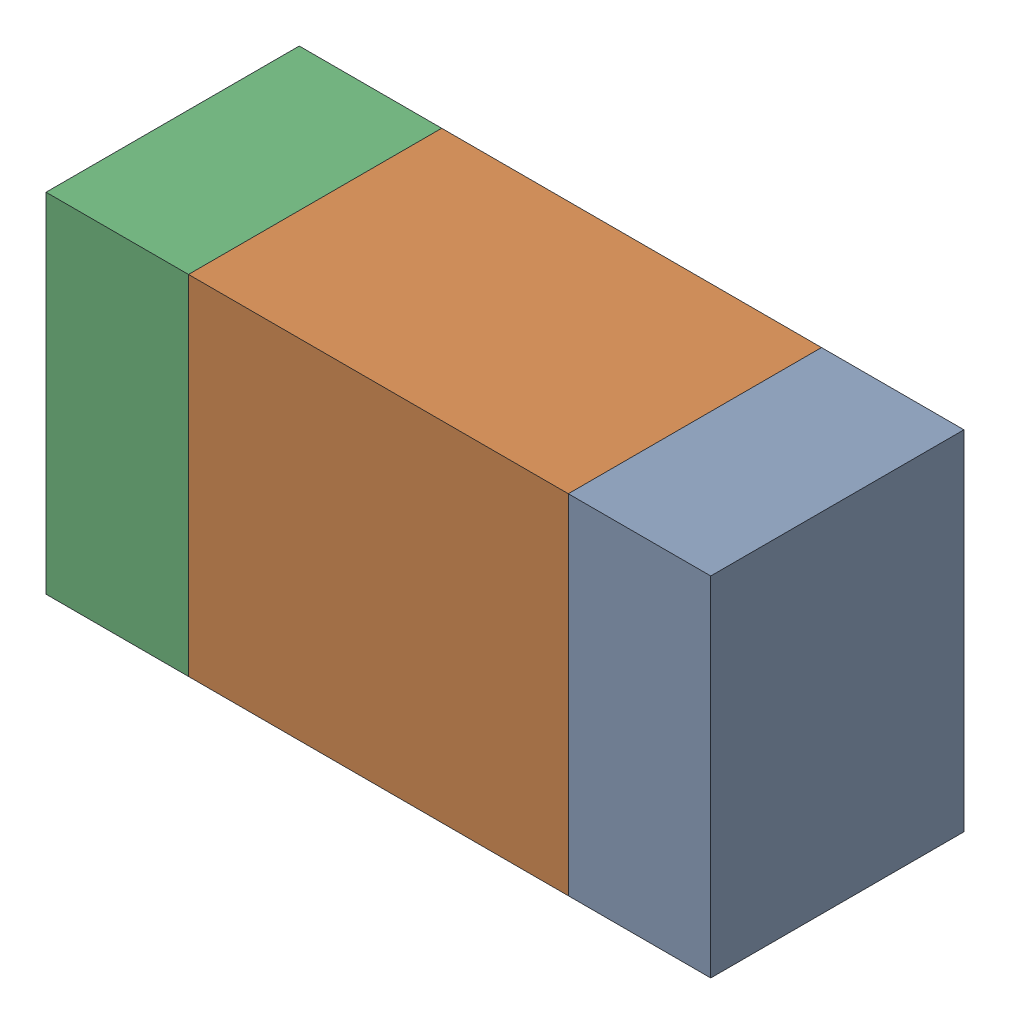
SolidWorks assembly R604_3PCB, configuration Default. Lengths in mm.
Overall size (1.05 0.55 0.4).
6 component instances, 2 part files, 0 mates.
Components (placement in the parent):
- 854785432-1: 854785432 [Default] at (101.5124 99.4001 -2.0638) size (0.22 0.55 0.4)
  - Extruded-1: Extruded [Default] at origin size (0.22 0.55 0.4)
- 854785568-1: 854785568 [Default] at (101.0999 99.4001 -2.0638) size (0.6 0.55 0.4)
  - Extruded_2-1: Extruded_2 [Default] at origin size (0.6 0.55 0.4)
- 854785432-2: 854785432 [Default] at (100.6874 99.4001 -2.0638) size (0.22 0.55 0.4)
  - Extruded-1: Extruded [Default] at origin size (0.22 0.55 0.4)
